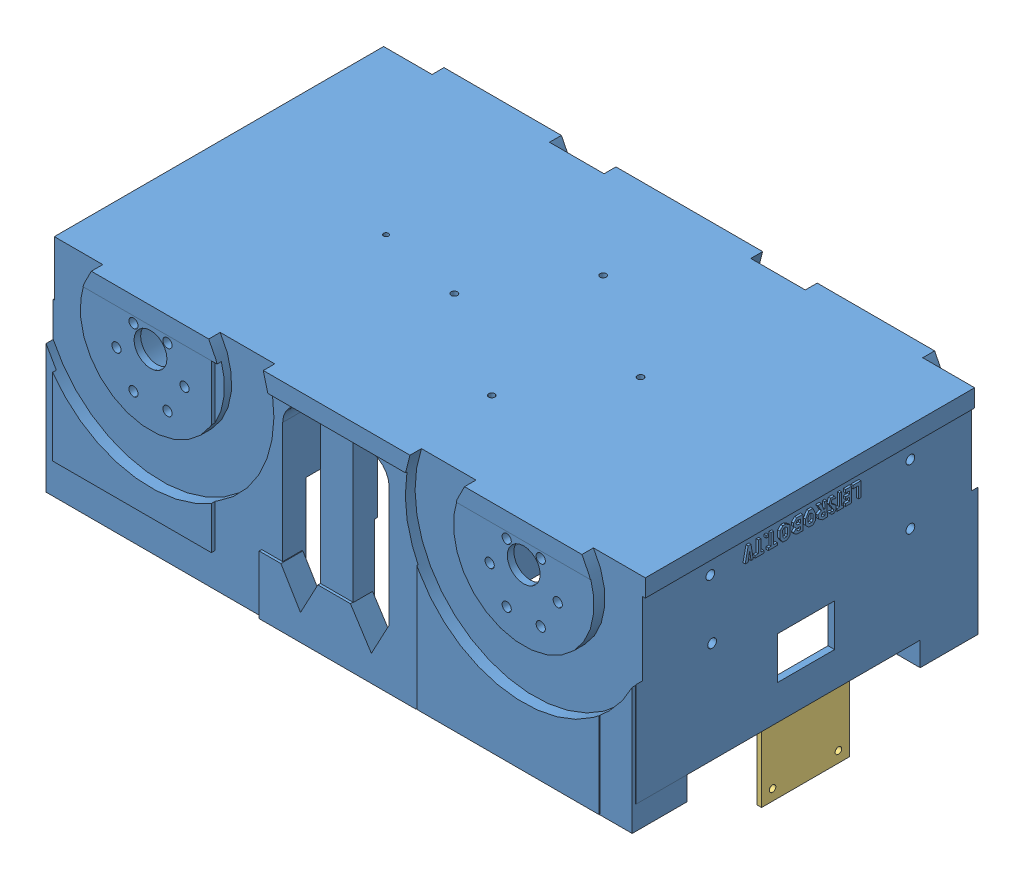
SolidWorks assembly ChassisAndPi, configuration Default. Lengths in mm.
Overall size (295.52 127.66 194.12).
3 component instances, 3 part files, 2 mates.
Components (placement in the parent):
- Chassis3ForSaleRelabeled-1: Chassis3ForSaleRelabeled [Default] at (-57.1096 172.6025 277.2688) size (295.52 106.02 194.12)
- RaspberryPi3-1: RaspberryPi3 [Default] at (30.653 188.0775 272.254) x (-0.838671 0 -0.544639) z (0 -1 0) size (89.64 57.31 18.92)
- ELP170DegreeCamera-1: ELP170DegreeCamera [Default] at (156.9485 115.7531 294.9882) x (0 -1 0) z (0 0 1) size (40 2 40)
Mates (geometry in assembly coordinates):
- Distance1: distance = 1 mm anti-aligned: plane of RaspberryPi3-1 through (38.1121 190.1775 246.9163) normal (0 1 0); plane of Chassis3ForSaleRelabeled-1 through (27.8904 189.1775 277.2688) normal (0 -1 0)
- Coincident1: coincident anti-aligned: plane of Chassis3ForSaleRelabeled-1 through (158.9485 172.6025 277.2688) normal (-1 0 0); plane of ELP170DegreeCamera-1 through (158.9485 115.7531 294.9882) normal (1 0 0)
